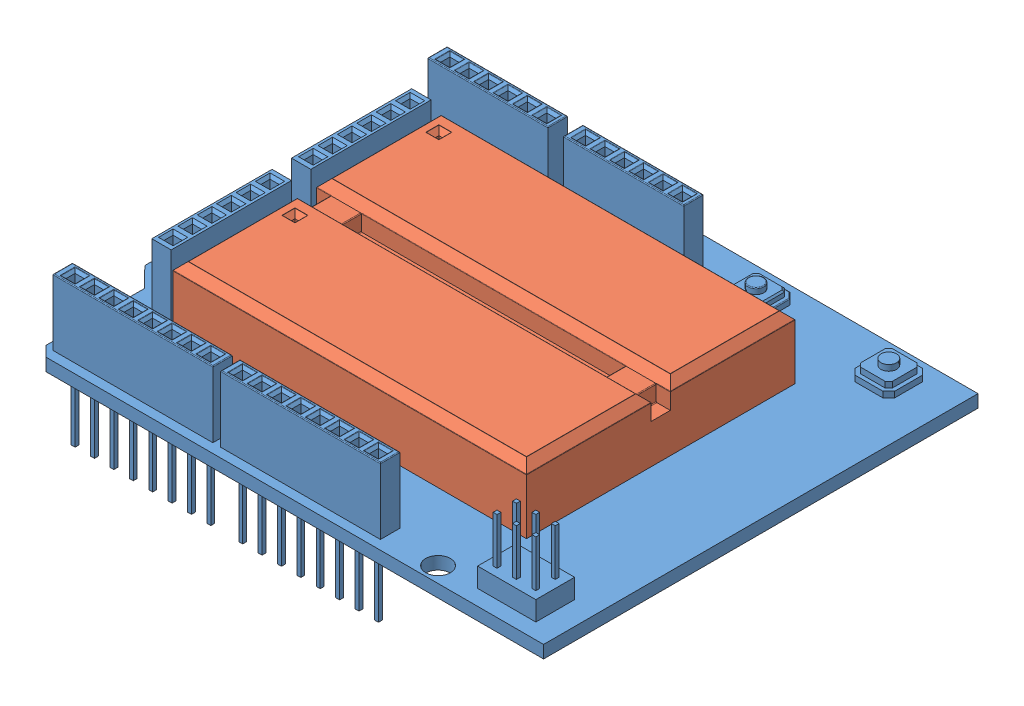
SolidWorks assembly Prototyping Shield-Simple, configuration Default. Lengths in mm.
Overall size (68 18.92 56).
2 component instances, 2 part files, 3 mates.
Components (placement in the parent):
- Arduino Prototyping Shield-1: Arduino Prototyping Shield [Default] at (18.3696 35.0162 55.7334) size (68 18.92 56)
- MiniBreadboard-Simple-1: MiniBreadboard-Simple [Default] at (16.6696 36.6462 55.7334) x (0 0 1) z (-1 0 0) size (34.6 8.15 45.6)
Mates (geometry in assembly coordinates):
- Coincident4: coincident: plane of Arduino Prototyping Shield-1 through (52.3696 36.6462 83.7334) normal (0 1 0); plane of MiniBreadboard-Simple-1 through (13.9243 36.6462 73.0334) normal (0 -1 0)
- Coincident5: coincident: plane of Arduino Prototyping Shield-1 through (18.3696 35.0162 55.7334) normal (0 0 1); plane of MiniBreadboard-Simple-1 through (36.7243 36.6462 55.7334) normal (0 0 1)
- Distance1: distance = 1 mm anti-aligned: plane of MiniBreadboard-Simple-1 through (-6.1304 44.7962 38.4334) normal (-1 0 0); plane of Arduino Prototyping Shield-1 through (-7.1304 45.1862 38.7334) normal (1 0 0)
